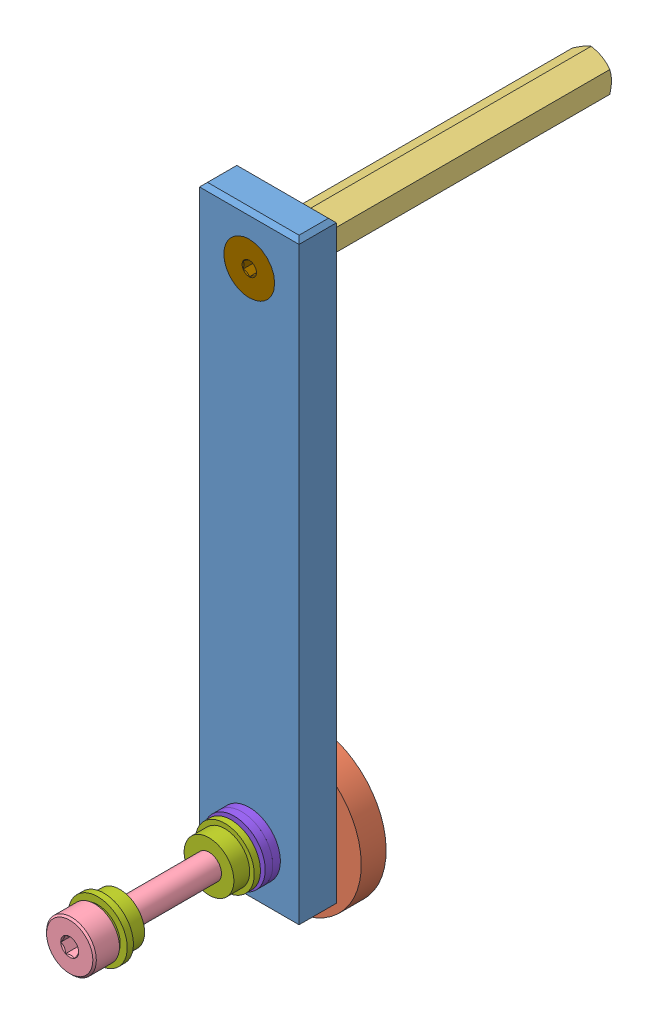
SolidWorks assembly top_link_assy, configuration Default. Lengths in mm.
Overall size (19.48 79.59 67.08).
13 component instances, 9 part files, 30 mates.
Components (placement in the parent):
- top_link-1: top_link [Default] at (0 -6.35 4.7625) x (0 1 0) z (-1 0 0) size (76.2 4.76 12.7)
- RC22-1: RC22 [Default] at (0 -69.85 -3.175) x (0.022662 -0.999743 0) z (-0.999743 -0.022662 0) size (19.05 3.17 19.05)
- _ALUM FEM THRDED HEX STANDOFF_91780A036-1: _ALUM FEM THRDED HEX STANDOFF_91780A036 [91780A036] at (0 -6.35 -20.0152) x (0.5 0.866025 0) z (0 0 1) size (4.76 5.5 38.96)
- 4_40-5-8_5-32-94035A136-1: 4_40-5-8_5-32-94035A136 [94035A136] at (0 -69.85 27.6772) x (0.8868 -0.462153 0) z (0 0 1) size (6.35 6.35 23.39)
- bearing_spacer_ 99040A316-1: bearing_spacer_ 99040A316 [Default] at (0 -69.85 7.0993) x (0.923728 0.383049 0) z (0 0 -1) size (4.76 4.76 0.41)
- bearing_spacer_ 99040A316-2: bearing_spacer_ 99040A316 [Default] at (0 -69.85 24.5022) x (0.923728 0.383049 0) z (0 0 -1) size (4.76 4.76 0.41)
- 4_40_THIN_LOCKNUT_90633A005-1: 4_40_THIN_LOCKNUT_90633A005 [90633A005] at (0 -69.85 -3.175) x (0.830959 0.556334 0) z (-0.556334 0.830959 0) size (6.35 2.86 7.33)
- FR144-ZZ-1: FR144-ZZ [Default] at (0 -69.85 21.2923) x (-0.97513 -0.221634 0) z (0 0 1) size (7.52 7.52 2.8)
- 4_40-Washer_AL_93286A005-new-1: 4_40-Washer_AL_93286A005-new [93286A005] at (0 -69.85 5.7277) x (0 0 -1) z (0.99868 -0.051372 0) size (0.97 7.92 7.92)
- 4_40-Washer_AL_93286A005-new-2: 4_40-Washer_AL_93286A005-new [93286A005] at (0 -69.85 6.6929) x (0 0 -1) z (0.987351 0.158553 0) size (0.97 7.92 7.92)
- FR144-ZZ-2: FR144-ZZ [Default] at (0 -69.85 9.9028) x (-0.778572 -0.627556 0) z (0 0 -1) size (7.52 7.52 2.8)
- 4_40-625-countersunk-stainless-92210a112-1: 4_40-625-countersunk-stainless-92210a112 [92210A112] at (0 -6.35 4.7625) size (6.48 6.48 16.22)
- 4_40-Washer_AL_93286A005-new-3: 4_40-Washer_AL_93286A005-new [93286A005] at (0 -6.35 -0.9652) x (0 0 1) z (-1 0 0) size (0.97 7.92 7.92)
Mates (geometry in assembly coordinates):
- Parallel1: parallel aligned: plane of top_link-1 through (-6.35 -6.35 0) normal (-1 0 0); plane of _ALUM FEM THRDED HEX STANDOFF_91780A036-1 through (-2.3813 -4.9752 -0.9652) normal (-1 0 0)
- Coincident12: coincident anti-aligned: plane of top_link-1 through (0 0 4.7625) normal (0 0 1); plane of ? through (-0.075 -2.7041 4.7625) normal (0 0 -1)
- Concentric12: concentric anti-aligned: cylinder of top_link-1 through (0 0 0) axis (0 0 -1) radius 1.632; cylinder of ? through (0 0 6.2611) axis (0 0 1) radius 2.7051
- Concentric17: concentric aligned: cylinder of top_link-1 through (0 -69.85 0) axis (0 0 -1) radius 1.632; cylinder of RC22-1 through (0 -69.85 0) axis (0 0 -1) radius 1.5875
- Coincident22: coincident anti-aligned: plane of top_link-1 through (0 -6.35 0) normal (0 0 -1); plane of RC22-1 through (0 -69.85 0) normal (0 0 1)
- Concentric14: concentric anti-aligned: cylinder of FR144-ZZ-2 through (0 -69.85 7.8867) axis (0 0 1) radius 1.5875; cylinder of RC22-1 through (0 -69.85 0) axis (0 0 -1) radius 1.5875
- Coincident23: coincident anti-aligned: plane of RC22-1 through (0 -69.85 -3.175) normal (0 0 -1); plane of 4_40_THIN_LOCKNUT_90633A005-1 through (0.4211 -76.186 -3.175) normal (0 0 1)
- Concentric18: concentric anti-aligned: cylinder of RC22-1 through (0 -69.85 0) axis (0 0 -1) radius 1.5875; cylinder of 4_40_THIN_LOCKNUT_90633A005-1 through (0 -69.85 -5.5663) axis (0 0 1) radius 1.1475
- Concentric13: concentric anti-aligned: circle of _ALUM FEM THRDED HEX STANDOFF_91780A036-1; circle of ?
- Concentric19: concentric aligned: cylinder of FR144-ZZ-1 through (0 -69.85 23.3084) axis (0 0 -1) radius 1.5875; cylinder of 4_40-5-8_5-32-94035A136-1 through (0 -69.85 4.6585) axis (0 0 -1) radius 1.5875
- Concentric23: concentric anti-aligned: cylinder of 4_40-5-8_5-32-94035A136-1 through (0 -69.85 4.6585) axis (0 0 -1) radius 1.5875; cylinder of 4_40-Washer_AL_93286A005-new-1 through (0 -69.85 4.7625) axis (0 0 1) radius 1.5875
- Concentric24: concentric anti-aligned: cylinder of 4_40-5-8_5-32-94035A136-1 through (0 -69.85 4.6585) axis (0 0 -1) radius 1.5875; cylinder of 4_40-Washer_AL_93286A005-new-2 through (0 -69.85 5.7277) axis (0 0 1) radius 1.5875
- Concentric15: concentric aligned: cylinder of FR144-ZZ-2 through (0 -69.85 7.8867) axis (0 0 1) radius 1.5875; cylinder of bearing_spacer_ 99040A316-1 through (0 -69.85 6.6929) axis (0 0 1) radius 1.5875
- Coincident18: coincident anti-aligned: plane of FR144-ZZ-2 through (0 -69.85 7.0993) normal (0 0 -1); plane of bearing_spacer_ 99040A316-1 through (0 -69.85 7.0993) normal (0 0 1)
- Concentric16: concentric anti-aligned: cylinder of FR144-ZZ-1 through (0 -69.85 23.3084) axis (0 0 -1) radius 1.5875; cylinder of bearing_spacer_ 99040A316-2 through (0 -69.85 24.0958) axis (0 0 1) radius 1.5875
- Coincident20: coincident anti-aligned: plane of FR144-ZZ-1 through (0 -69.85 24.0958) normal (0 0 1); plane of bearing_spacer_ 99040A316-2 through (0 -69.85 24.0958) normal (0 0 -1)
- Coincident31: coincident anti-aligned: plane of 4_40-Washer_AL_93286A005-new-1 through (0 -69.85 5.7277) normal (0 0 1); plane of 4_40-Washer_AL_93286A005-new-2 through (0 -69.85 5.7277) normal (0 0 -1)
- Concentric25: concentric anti-aligned: cylinder of 4_40-5-8_5-32-94035A136-1 through (0 -69.85 4.6585) axis (0 0 -1) radius 1.5875; cylinder of FR144-ZZ-2 through (0 -69.85 7.8867) axis (0 0 1) radius 1.5875
- Symmetric1: symmetric aligned: plane of top_link-1 through (-6.35 -6.35 0) normal (-1 0 0); plane of top_link-1 through (6.35 -6.35 0) normal (1 0 0); plane of assembly through (0 0 0) normal (1 0 0)
- Coincident34: coincident anti-aligned: plane of top_link-1 through (0 -6.35 0) normal (0 0 -1); plane of assembly through (0 0 0) normal (0 0 1)
- Coincident35: coincident anti-aligned: plane of 4_40-5-8_5-32-94035A136-1 through (-1.4673 -72.6656 24.5022) normal (0 0 -1); plane of bearing_spacer_ 99040A316-2 through (0 -69.85 24.5022) normal (0 0 1)
- Coincident36: coincident anti-aligned: plane of top_link-1 through (0 -6.35 4.7625) normal (0 0 1); plane of 4_40-Washer_AL_93286A005-new-1 through (0 -69.85 4.7625) normal (0 0 -1)
- Coincident37: coincident anti-aligned: plane of bearing_spacer_ 99040A316-1 through (0 -69.85 6.6929) normal (0 0 -1); plane of 4_40-Washer_AL_93286A005-new-2 through (0 -69.85 6.6929) normal (0 0 1)
- Concentric26: concentric aligned: cylinder of top_link-1 through (0 -6.35 4.7625) axis (0 0 1) radius 1.632; cylinder of 4_40-625-countersunk-stainless-92210a112-1 through (0 -6.35 4.7625) axis (0 0 1) radius 3.2385
- Coincident38: coincident aligned: plane of top_link-1 through (0 -6.35 4.7625) normal (0 0 1); plane of 4_40-625-countersunk-stainless-92210a112-1 through (0 -7.7724 4.7625) normal (0 0 1)
- Concentric27: concentric anti-aligned: cylinder of top_link-1 through (0 -6.35 4.7625) axis (0 0 1) radius 1.632; circle of _ALUM FEM THRDED HEX STANDOFF_91780A036-1
- Coincident39: coincident anti-aligned: plane of _ALUM FEM THRDED HEX STANDOFF_91780A036-1 through (-2.3813 -4.9752 -0.9652) normal (0 0 1); plane of 4_40-Washer_AL_93286A005-new-3 through (0 -6.35 -0.9652) normal (0 0 -1)
- Coincident40: coincident anti-aligned: plane of top_link-1 through (0 -6.35 0) normal (0 0 -1); plane of 4_40-Washer_AL_93286A005-new-3 through (0 -6.35 0) normal (0 0 1)
- Concentric28: concentric anti-aligned: cylinder of top_link-1 through (0 -6.35 4.7625) axis (0 0 1) radius 1.632; cylinder of 4_40-Washer_AL_93286A005-new-3 through (0 -6.35 0) axis (0 0 -1) radius 1.5875
- Coincident41: coincident aligned: plane of top_link-1 through (0 0 0) normal (0 1 0); plane of assembly through (0 0 0) normal (0 1 0)
